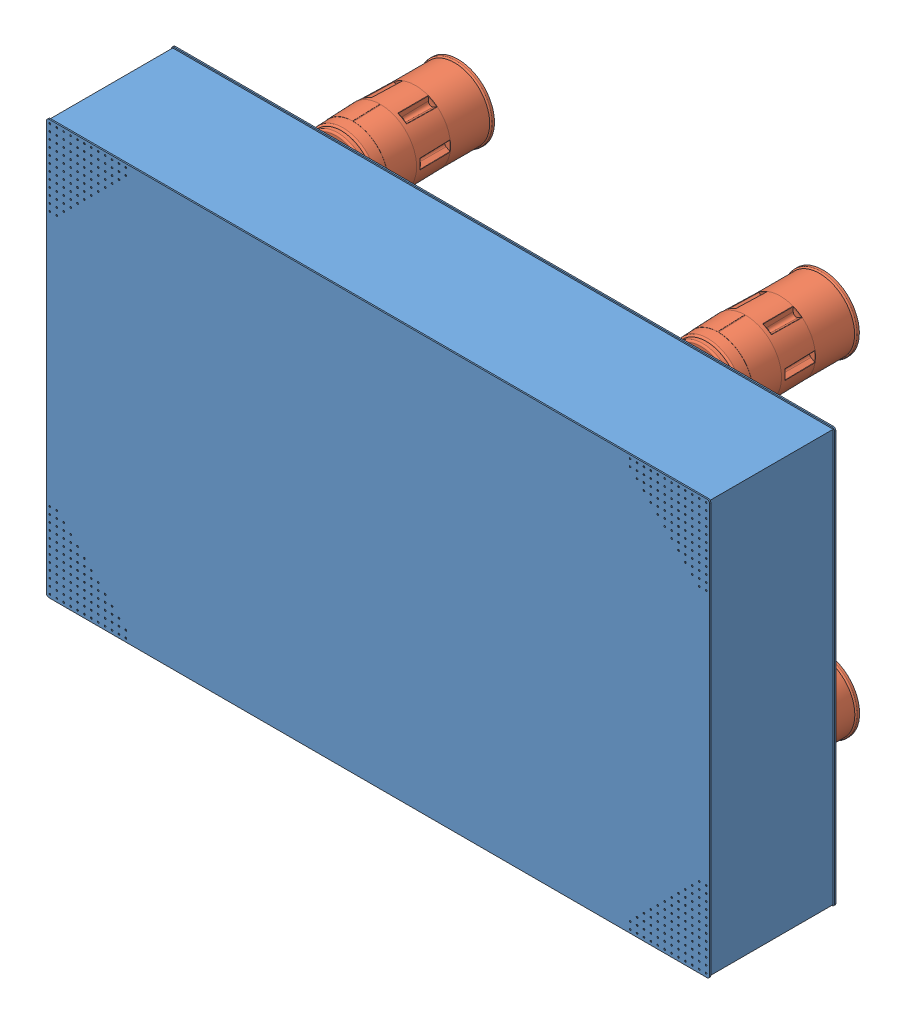
SolidWorks assembly table_with_legs, configuration Default. Lengths in mm.
Overall size (2400 1500 950.88).
5 component instances, 2 part files, 12 mates.
Components (placement in the parent):
- M-RS-58-18-1: M-RS-58-18 [Default] at (-679.8721 921.2576 1141.4726) x (1 0 0) z (0 -1 0) size (2400 457 1500)
- S-2000-119.5-2: S-2000-119.5 [-000] at (-19.6071 1517.7497 633.0884) size (263.3 283.03 493.88)
- S-2000-119.5-3: S-2000-119.5 [-000] at (-1340.137 1517.7497 633.0884) size (263.3 283.03 493.88)
- S-2000-119.5-4: S-2000-119.5 [-000] at (-1340.137 324.7654 633.0884) size (263.3 283.03 493.88)
- S-2000-119.5-5: S-2000-119.5 [-000] at (-19.5524 324.568 632.301) size (263.3 283.03 493.88)
Mates (geometry in assembly coordinates):
- Coincident4: coincident anti-aligned: plane of M-RS-58-18-1 through (-1870.2201 180.9096 684.4726) normal (0 0 -1); plane of S-2000-119.5-2 through (-19.6071 1517.7497 684.4726) normal (0 0 1)
- Coincident5: coincident anti-aligned: plane of M-RS-58-18-1 through (-1870.2201 180.9096 684.4726) normal (0 0 -1); plane of S-2000-119.5-3 through (-1340.137 1517.7497 684.4726) normal (0 0 1)
- Coincident6: coincident anti-aligned: plane of M-RS-58-18-1 through (-1870.2201 180.9096 684.4726) normal (0 0 -1); plane of S-2000-119.5-4 through (-1340.137 324.7654 684.4726) normal (0 0 1)
- Distance1: distance = 153 mm: point of S-2000-119.5-4; line of M-RS-58-18-1 through (515.1279 176.2576 689.2726) axis (-1 0 0)
- Distance2: distance = 536 mm: line of M-RS-58-18-1 through (-1874.8721 176.2576 689.2726) axis (0 1 0); point of S-2000-119.5-4
- Distance3: distance = 153 mm: point of S-2000-119.5-3; line of M-RS-58-18-1 through (-1874.8721 1666.2576 689.2726) axis (1 0 0)
- Distance4: distance = 536 mm: line of M-RS-58-18-1 through (-1874.8721 176.2576 689.2726) axis (0 1 0); point of S-2000-119.5-3
- Distance6: distance = 536 mm: point of S-2000-119.5-2; line of M-RS-58-18-1 through (515.1279 1666.2576 689.2726) axis (0 -1 0)
- Distance7: distance = 153 mm: point of S-2000-119.5-2; line of M-RS-58-18-1 through (-1874.8721 1666.2576 689.2726) axis (1 0 0)
- Coincident17: coincident anti-aligned: plane of M-RS-58-18-1 through (-1870.2201 180.9096 684.4726) normal (0 0 -1); plane of S-2000-119.5-5 through (-51.282 276.2989 684.4726) normal (0 0 1)
- Distance10: distance = 153 mm: point of S-2000-119.5-5; line of M-RS-58-18-1 through (515.1279 176.2576 689.2726) axis (-1 0 0)
- Distance11: distance = 536 mm: point of S-2000-119.5-5; line of M-RS-58-18-1 through (515.1279 1666.2576 689.2726) axis (0 -1 0)
